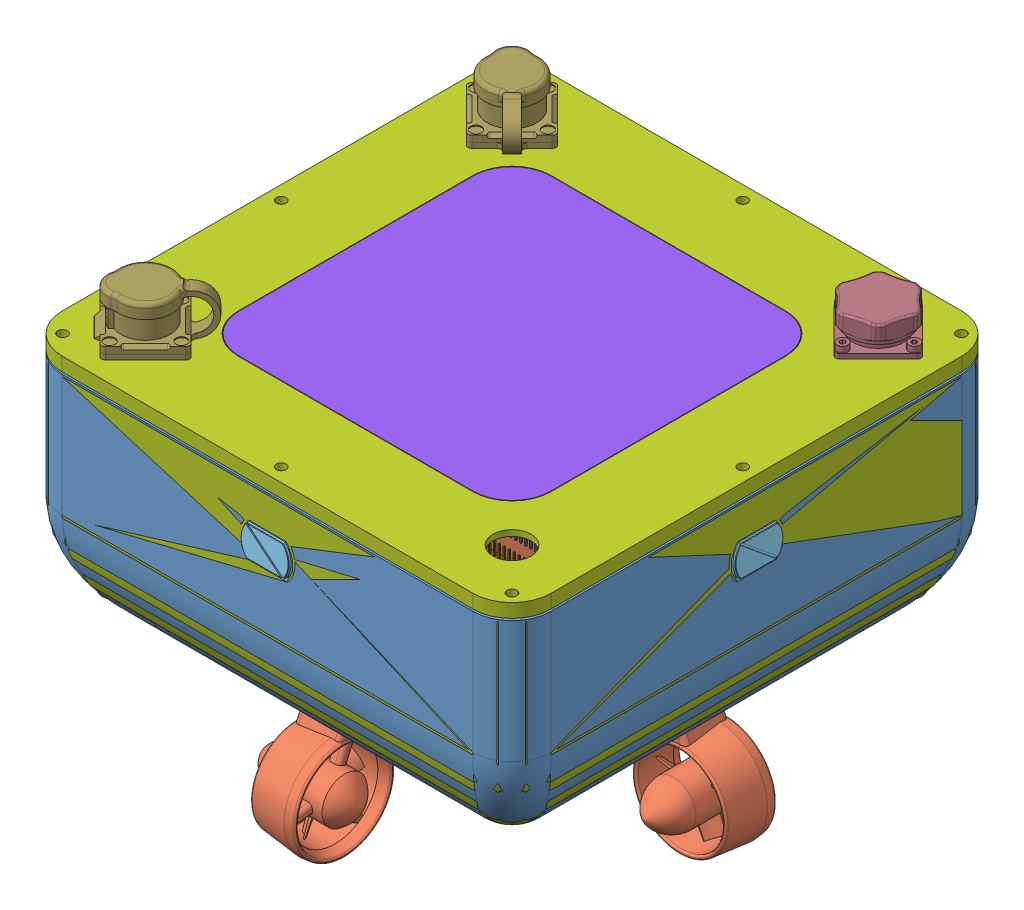
SolidWorks assembly 总装配新v2, configuration 默认. Lengths in mm.
Overall size (263.57 208.9 263.57).
33 component instances, 13 part files, 42 mates.
Components (placement in the parent):
- 一体船体v2-1: 一体船体v2 [默认] at (-39.6363 55.6113 0) size (250 127 250)
- 推进器-1: 推进器 [默认] at (-27.6363 -88.1292 97.6034) x (0 -0.396648 -0.917971) z (-1 0 0) size (52 59.5 50)
- 舵机组合-1: 舵机组合 [默认] at (26.1859 24.6537 61) size (49 60.81 86)
  - 舵机连接件-1: 舵机连接件 [默认] at (-65.8222 -4.5425 -5) size (49 59 10)
  - 35kg舵机-1: 35kg舵机 [默认] at (-65.8222 5.9575 17.5) x (0 1 0) z (1 0 0) size (54 43 20)
  - magswitch-1: magswitch [默认] at (-65.8222 5.9575 41) x (0 0 1) z (-1 0 0) size (35.5 16.3 39)
  - 舵盘联轴器-1: 舵盘联轴器 [默认] at (-65.8222 5.9575 17.5) x (0.940481 -0.339847 0) z (0 0 1) size (32.5 32.5 22)
- 舵机组合-2: 舵机组合 [默认] at (-105.4585 24.6537 -61) x (-1 0 0) z (0 0 -1) size (49 60.81 86)
  - 舵机连接件-1: 舵机连接件 [默认] at (-65.8222 -4.5425 -5) size (49 59 10)
  - 35kg舵机-1: 35kg舵机 [默认] at (-65.8222 5.9575 17.5) x (0 1 0) z (1 0 0) size (54 43 20)
  - magswitch-1: magswitch [默认] at (-65.8222 5.9575 41) x (0 0 1) z (-1 0 0) size (35.5 16.3 39)
  - 舵盘联轴器-1: 舵盘联轴器 [默认] at (-65.8222 5.9575 17.5) x (0.940481 -0.339847 0) z (0 0 1) size (32.5 32.5 22)
- 舵机组合-3: 舵机组合 [默认] at (21.3637 24.6537 -65.8222) x (0 0 -1) z (1 0 0) size (49 60.81 86)
  - 舵机连接件-1: 舵机连接件 [默认] at (-65.8222 -4.5425 -5) size (49 59 10)
  - 35kg舵机-1: 35kg舵机 [默认] at (-65.8222 5.9575 17.5) x (0 1 0) z (1 0 0) size (54 43 20)
  - magswitch-1: magswitch [默认] at (-65.8222 5.9575 41) x (0 0 1) z (-1 0 0) size (35.5 16.3 39)
  - 舵盘联轴器-1: 舵盘联轴器 [默认] at (-65.8222 5.9575 17.5) x (0.940481 -0.339847 0) z (0 0 1) size (32.5 32.5 22)
- 舵机组合-4: 舵机组合 [默认] at (-100.6363 24.6537 65.8222) x (0 0 1) z (-1 0 0) size (49 60.81 86)
  - 舵机连接件-1: 舵机连接件 [默认] at (-65.8222 -4.5425 -5) size (49 59 10)
  - 35kg舵机-1: 35kg舵机 [默认] at (-65.8222 5.9575 17.5) x (0 1 0) z (1 0 0) size (54 43 20)
  - magswitch-1: magswitch [默认] at (-65.8222 5.9575 41) x (0 0 1) z (-1 0 0) size (35.5 16.3 39)
  - 舵盘联轴器-1: 舵盘联轴器 [默认] at (-65.8222 5.9575 17.5) x (0.940481 -0.339847 0) z (0 0 1) size (32.5 32.5 22)
- 推进器-2: 推进器 [默认] at (57.967 -88.1292 -12) x (-0.917971 -0.396648 0) z (0 0 1) size (52 59.5 50)
- 推进器-3: 推进器 [默认] at (-137.2397 -88.1292 12) x (0.917971 -0.396648 0) z (0 0 -1) size (52 59.5 50)
- 推进器-4: 推进器 [默认] at (-51.6363 -88.1292 -97.6034) x (0 -0.396648 0.917971) z (1 0 0) size (52 59.5 50)
- 船体顶盖-1: 船体顶盖 [默认] at (-39.6363 54.6113 0) size (250 134 250)
- 亚克力顶盖-1: 亚克力顶盖 [默认] at (-39.6363 60.6113 0) size (159.5 3 159.5)
- raspberry_p4b_v001-1: raspberry_p4b_v001 [Standard] at (27.5191 -67.4658 41.4433) x (1 0 0) z (0 1 0) size (90.11 58.5 18.59)
- Grove-mega-shield-2: Grove-mega-shield [默认] at (-37.6326 -28.7603 -34.4009) size (92.5 20.2 57.5)
- 12v锂电新-1: 12v锂电新 [默认] at (-41.5612 -57.3833 -0.6675) size (64 17 121.5)
- hdmi航插-2: hdmi航插 [默认] at (-133.3226 66.1113 -93.6863) x (-0.707107 0 0.707107) z (-0.707107 0 -0.707107) size (33 22.98 45.76)
- hdmi航插-3: hdmi航插 [默认] at (-133.3226 66.1113 93.6863) x (0.707107 0 0.707107) z (-0.707107 0 0.707107) size (33 22.98 45.76)
- 充电航插-1: 充电航插 [默认] at (54.05 63.6113 -93.6863) x (0.707107 0 -0.707107) z (0.707107 0 0.707107) size (32 15.75 34)
Mates (geometry in assembly coordinates):
- 重合8: coincident anti-aligned: plane of 一体船体v2-1 through (-51.6363 -71.6779 55.0007) normal (0 -0.917971 0.396648); plane of 推进器-1 through (-27.6363 -58.7541 84.9106) normal (0 0.917971 -0.396648)
- 重合12: coincident anti-aligned: plane of 一体船体v2-1 through (-27.6363 -71.6779 -55.0007) normal (0 -0.917971 -0.396648); plane of 推进器-4 through (-51.6363 -58.7541 -84.9106) normal (0 0.917971 0.396648)
- 重合13: coincident anti-aligned: plane of 一体船体v2-1 through (15.3644 -71.6779 12) normal (0.396648 -0.917971 0); plane of 推进器-2 through (45.2743 -58.7541 -12) normal (-0.396648 0.917971 0)
- 同心18: concentric aligned: cylinder of 一体船体v2-1 through (56.3551 -64.8598 0) axis (-0.396648 0.917971 0) radius 1.5; cylinder of 推进器-2 through (51.7936 -54.3031 0) axis (-0.396648 0.917971 0) radius 1.25
- 同心19: concentric aligned: cylinder of 一体船体v2-1 through (42.1265 -71.0078 0) axis (-0.396648 0.917971 0) radius 1.5; cylinder of 推进器-2 through (37.5651 -60.4512 0) axis (-0.396648 0.917971 0) radius 1.25
- 同心20: concentric aligned: cylinder of 一体船体v2-1 through (-39.6363 -64.8598 95.9914) axis (0 0.917971 -0.396648) radius 1.5; cylinder of 推进器-1 through (-39.6363 -54.3031 91.4299) axis (0 0.917971 -0.396648) radius 1.25
- 同心21: concentric aligned: cylinder of 一体船体v2-1 through (-39.6363 -71.0078 81.7628) axis (0 0.917971 -0.396648) radius 1.5; cylinder of 推进器-1 through (-39.6363 -60.4512 77.2014) axis (0 0.917971 -0.396648) radius 1.25
- 同心22: concentric aligned: cylinder of 一体船体v2-1 through (-39.6363 -71.0078 -81.7628) axis (0 0.917971 0.396648) radius 1.5; cylinder of 推进器-4 through (-39.6363 -60.4512 -77.2014) axis (0 0.917971 0.396648) radius 1.25
- 同心23: concentric aligned: cylinder of 一体船体v2-1 through (-39.6363 -64.8598 -95.9914) axis (0 0.917971 0.396648) radius 1.5; cylinder of 推进器-4 through (-39.6363 -54.3031 -91.4299) axis (0 0.917971 0.396648) radius 1.25
- 重合14: coincident anti-aligned: plane of 一体船体v2-1 through (-94.637 -71.6779 -12) normal (-0.396648 -0.917971 0); plane of 推进器-3 through (-124.5469 -58.7541 12) normal (0.396648 0.917971 0)
- 同心24: concentric aligned: cylinder of 一体船体v2-1 through (-135.6277 -64.8598 0) axis (0.396648 0.917971 0) radius 1.5; cylinder of 推进器-3 through (-131.0662 -54.3031 0) axis (0.396648 0.917971 0) radius 1.25
- 同心25: concentric aligned: cylinder of 一体船体v2-1 through (-121.3991 -71.0078 0) axis (0.396648 0.917971 0) radius 1.5; cylinder of 推进器-3 through (-116.8377 -60.4512 0) axis (0.396648 0.917971 0) radius 1.25
- 重合16: coincident aligned: line of 一体船体v2-1 through (125 -39.6363 55.6113) axis (0 0 -1); line of 船体顶盖-1 through (125 -39.6363 54.6113) axis (0 0 -1)
- 平行2: parallel aligned: plane of 一体船体v2-1 through (85.3637 -69.3887 125) normal (1 0 0); plane of 船体顶盖-1 through (85.3637 60.6113 0) normal (1 0 0)
- 距离1: distance = 1 mm anti-aligned: plane of 一体船体v2-1 through (-39.6363 55.6113 0) normal (0 1 0); plane of 船体顶盖-1 through (-39.6363 56.6113 0) normal (0 -1 0)
- 重合17: coincident aligned: line of 一体船体v2-1 through (125 -39.6363 55.6113) axis (0 0 -1); line of 亚克力顶盖-1 through (3 -39.6363 63.6113) axis (0 0 -1)
- 重合18: coincident anti-aligned: plane of 船体顶盖-1 through (-39.6363 60.6113 0) normal (0 1 0); plane of 亚克力顶盖-1 through (-39.6363 60.6113 0) normal (0 -1 0)
- 平行3: parallel anti-aligned: plane of 船体顶盖-1 through (20.3637 40.6113 80) normal (0 0 -1); plane of 亚克力顶盖-1 through (40.1137 63.6113 79.75) normal (0 0 1)
- 重合19: coincident anti-aligned: plane of 一体船体v2-1 through (-39.6363 -9.3887 0) normal (0 1 0); plane of 舵机组合-4/舵机连接件-1 through (-105.6363 -9.3887 0) normal (0 -1 0)
- 重合20: coincident anti-aligned: plane of 一体船体v2-1 through (-39.6363 -9.3887 0) normal (0 1 0); plane of 舵机组合-1/舵机连接件-1 through (-39.6363 -9.3887 66) normal (0 -1 0)
- 重合21: coincident anti-aligned: plane of 一体船体v2-1 through (-39.6363 -9.3887 0) normal (0 1 0); plane of 舵机组合-3/舵机连接件-1 through (26.3637 -9.3887 0) normal (0 -1 0)
- 重合22: coincident anti-aligned: plane of 一体船体v2-1 through (-39.6363 -9.3887 0) normal (0 1 0); plane of 舵机组合-2/舵机连接件-1 through (-39.6363 -9.3887 -66) normal (0 -1 0)
- 同心26: concentric aligned: cylinder of 一体船体v2-1 through (-59.1363 -19.3887 -61) axis (0 1 0) radius 2.25; cylinder of 舵机组合-2/舵机连接件-1 through (-59.1363 -15.3887 -61) axis (0 1 0) radius 2.25
- 同心27: concentric aligned: cylinder of 一体船体v2-1 through (-20.1363 -19.3887 -61) axis (0 1 0) radius 2.25; cylinder of 舵机组合-2/舵机连接件-1 through (-20.1363 -15.3887 -61) axis (0 1 0) radius 2.25
- 同心28: concentric aligned: cylinder of 一体船体v2-1 through (-100.6363 -19.3887 19.5) axis (0 1 0) radius 2.25; circle of 舵机组合-4/舵机连接件-1
- 同心29: concentric aligned: cylinder of 一体船体v2-1 through (-100.6363 -19.3887 -19.5) axis (0 1 0) radius 2.25; cylinder of 舵机组合-4/舵机连接件-1 through (-100.6363 -15.3887 -19.5) axis (0 1 0) radius 2.25
- 同心30: concentric aligned: cylinder of 一体船体v2-1 through (-59.1363 -19.3887 61) axis (0 1 0) radius 2.25; cylinder of 舵机组合-1/舵机连接件-1 through (-59.1363 -15.3887 61) axis (0 1 0) radius 2.25
- 同心31: concentric aligned: cylinder of 一体船体v2-1 through (-20.1363 -19.3887 61) axis (0 1 0) radius 2.25; cylinder of 舵机组合-1/舵机连接件-1 through (-20.1363 -15.3887 61) axis (0 1 0) radius 2.25
- 同心32: concentric aligned: cylinder of 一体船体v2-1 through (21.3637 -19.3887 -19.5) axis (0 1 0) radius 2.25; cylinder of 舵机组合-3/舵机连接件-1 through (21.3637 -15.3887 -19.5) axis (0 1 0) radius 2.25
- 同心34: concentric aligned: cylinder of 一体船体v2-1 through (21.3637 -19.3887 19.5) axis (0 1 0) radius 2.25; circle of 舵机组合-3/舵机连接件-1
- 重合23: coincident anti-aligned: plane of 船体顶盖-1 through (-144.6363 63.6113 -105) normal (0 1 0); plane of hdmi航插-1 through (74.5561 63.6113 -93.6863) normal (0 -1 0)
- 同心35: concentric aligned: cylinder of 船体顶盖-1 through (54.05 60.6113 -75.3015) axis (0 1 0) radius 1.75; cylinder of hdmi航插-1 through (54.05 68.9613 -75.3015) axis (0 1 0) radius 2.8
- 同心36: concentric aligned: cylinder of 船体顶盖-1 through (35.6652 60.6113 -93.6863) axis (0 1 0) radius 1.75; cylinder of hdmi航插-1 through (35.6652 68.9613 -93.6863) axis (0 1 0) radius 2.8
- 重合24: coincident anti-aligned: plane of 船体顶盖-1 through (-144.6363 63.6113 -105) normal (0 1 0); plane of hdmi航插-2 through (-133.3226 63.6113 -114.1924) normal (0 -1 0)
- 同心37: concentric aligned: cylinder of 船体顶盖-1 through (-133.3226 60.6113 -75.3015) axis (0 1 0) radius 1.75; cylinder of hdmi航插-2 through (-133.3226 68.9613 -75.3015) axis (0 1 0) radius 2.8
- 同心38: concentric aligned: cylinder of 船体顶盖-1 through (-114.9378 60.6113 -93.6863) axis (0 1 0) radius 1.75; circle of hdmi航插-2
- 重合25: coincident anti-aligned: plane of 船体顶盖-1 through (-144.6363 63.6113 -105) normal (0 1 0); plane of hdmi航插-3 through (-153.8287 63.6113 93.6863) normal (0 -1 0)
- 同心39: concentric aligned: cylinder of 船体顶盖-1 through (-133.3226 60.6113 75.3015) axis (0 1 0) radius 1.75; cylinder of hdmi航插-3 through (-133.3226 68.9613 75.3015) axis (0 1 0) radius 2.8
- 同心40: concentric aligned: cylinder of 船体顶盖-1 through (-114.9378 60.6113 93.6863) axis (0 1 0) radius 1.75; cylinder of hdmi航插-3 through (-114.9378 68.9613 93.6863) axis (0 1 0) radius 2.8
- 重合26: coincident anti-aligned: plane of 船体顶盖-1 through (-144.6363 63.6113 -105) normal (0 1 0); plane of 充电航插-1 through (54.05 63.6113 -73.8873) normal (0 -1 0)
- 同心41: concentric anti-aligned: cylinder of 船体顶盖-1 through (54.05 60.6113 -75.3015) axis (0 1 0) radius 1.75; cylinder of 充电航插-1 through (54.05 69.1113 -75.3015) axis (0 -1 0) radius 2.8
- 同心42: concentric anti-aligned: cylinder of 船体顶盖-1 through (72.4348 60.6113 -93.6863) axis (0 1 0) radius 1.75; cylinder of 充电航插-1 through (72.4348 69.1113 -93.6863) axis (0 -1 0) radius 2.8
